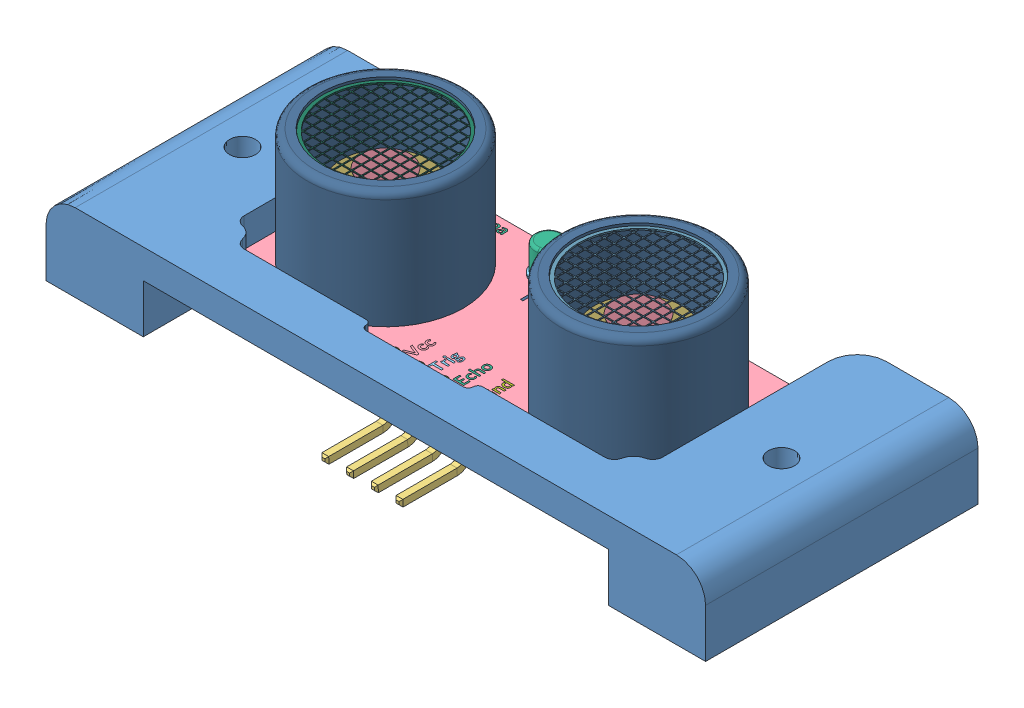
SolidWorks assembly Ultrasonic Assembly, configuration Default. Lengths in mm.
Overall size (67.8 17.46 29.57).
64 component instances, 62 part files, 11 mates.
Components (placement in the parent):
- Ultrasonic Bracket-1: Ultrasonic Bracket [Default] at (0.0374 -5.7361 0.0102) x (-1 0 0) z (0 0 1) size (67.8 8 28)
- HCSR04 Ultrasonic Sensor.stp-1: HCSR04 Ultrasonic Sensor.stp [Default] at (0.0374 -9.7361 0.0102) x (1 0 0) z (0 1 0) size (45 25.57 17.46)
  - HC-04Array.stp-1: HC-04Array.stp [Default] at origin size (10.16 2.54 2.54)
  - HC-04Array001.stp-1: HC-04Array001.stp [Default] at (0 0 1) size (8.32 7.52 6.46)
  - HC-04Placa.stp-1: HC-04Placa.stp [Default] at origin size (45 20 1)
  - HC-04Pad003.stp-1: HC-04Pad003.stp [Default] at (0 0 1) size (10.52 3.38 0.2)
  - HC-04Fillet.stp-1: HC-04Fillet.stp [Default] at (0 0 1) size (10.1 2.84 3)
  - HC-04Array002.stp-1: HC-04Array002.stp [Default] at origin size (9.62 2 1)
  - HC-04Array003.stp-1: HC-04Array003.stp [Default] at (0 0 1) size (28 12 0.8)
  - HC-04Fusion.stp-1: HC-04Fusion.stp [Default] at origin size (6 2 1)
  - HC-04Fillet001.stp-1: HC-04Fillet001.stp [Default] at (0 0 1) size (42 16 12)
  - HC-04Pad005.stp-1: HC-04Pad005.stp [Default] at (0 0 1) size (39.16 13 0.2)
  - HC-04Pad006.stp-1: HC-04Pad006.stp [Default] at (0 0 1) size (35.01 9.04 7)
  - HC-04Fusion001.stp-1: HC-04Fusion001.stp [Default] at (0 0 8) size (31 5 1.5)
  - HC-04Clone_of_Fusion002.stp-1: HC-04Clone_of_Fusion002.stp [Default] at (47.2 -5.5 12.6) size (13 13 0.15)
  - HC-04Clone_of_Fusion003.stp-1: HC-04Clone_of_Fusion003.stp [Default] at (21.2 -5.5 12.6) size (13 13 0.15)
  - HC-04Array005.stp-1: HC-04Array005.stp [Default] at origin size (9.62 2 1)
  - HC-04Array002002.stp-1: HC-04Array002002.stp [Default] at (-5.9 0.1 0.15) size (6.57 1.4 0.56)
  - HC-04Clone_of_Array002002.stp-1: HC-04Clone_of_Array002002.stp [Default] at (-23.9 0.1 0.15) size (6.57 1.4 0.56)
  - HC-04Array002003.stp-1: HC-04Array002003.stp [Default] at (-6.05 0 0.15) size (6.57 1.4 0.56)
  - HC-04Clone_of_Array002003.stp-1: HC-04Clone_of_Array002003.stp [Default] at (-24.05 0 0.15) size (6.57 1.4 0.56)
  - HC-04Integrados.stp-1: HC-04Integrados.stp [Default] at origin size (42.14 9 1)
  - HC-04ShapeString.stp-1: HC-04ShapeString.stp [Default] at (-3.2 -7 1.01) x (0 1 0) z (0 0 1) size (2.53 1.13 0.01)
  - HC-04ShapeString001.stp-1: HC-04ShapeString001.stp [Default] at (-0.6 -7 1.01) x (0 1 0) z (0 0 1) size (2.66 1.45 0.01)
  - HC-04ShapeString002.stp-1: HC-04ShapeString002.stp [Default] at (1.9 -7 1.01) x (0 1 0) z (0 0 1) size (3.21 1.16 0.01)
  - HC-04ShapeString003.stp-1: HC-04ShapeString003.stp [Default] at (4.5 -7 1.01) x (0 1 0) z (0 0 1) size (2.71 1.16 0.01)
  - HC-04ShapeString004.stp-1: HC-04ShapeString004.stp [Default] at (-19.5 -9.3 1.01) size (1.84 2.34 0.01)
  - HC-04ShapeString005.stp-1: HC-04ShapeString005.stp [Default] at (17.5 -9.3 1.01) size (1.82 2.34 0.01)
  - HC-04ShapeString006.stp-1: HC-04ShapeString006.stp [Default] at (-3 3.7 1.01) size (5.52 1.41 0.01)
  - HC-04Pad008.stp-1: HC-04Pad008.stp [Default] at (0 0 -0.01) size (44.56 19.6 1.02)
  - HC-04Scale004.stp-1: HC-04Scale004.stp [Default] at (-1.9 -21.5 -1.5) x (0 1 0) z (0 0 1) size (0.8 1.77 0.5)
  - HC-04Scale027.stp-1: HC-04Scale027.stp [Default] at (-1.9 -10.2323 -1.5) x (0 1 0) z (0 0 1) size (0.8 1.77 0.5)
  - HC-04Scale028.stp-1: HC-04Scale028.stp [Default] at (8.5984 -21.5 -1.5) x (0 1 0) z (0 0 1) size (0.8 1.77 0.5)
  - HC-04Scale029.stp-1: HC-04Scale029.stp [Default] at (8.5984 -19.5867 -1.5) x (0 1 0) z (0 0 1) size (0.8 1.77 0.5)
  - HC-04Scale030.stp-1: HC-04Scale030.stp [Default] at (8.5984 -17.5982 -1.5) x (0 1 0) z (0 0 1) size (0.8 1.77 0.5)
  - HC-04Scale031.stp-1: HC-04Scale031.stp [Default] at (8.5984 -15.6427 -1.5) x (0 1 0) z (0 0 1) size (0.8 1.77 0.5)
  - HC-04Scale032.stp-1: HC-04Scale032.stp [Default] at (8.5984 -11.6848 -1.5) x (0 1 0) z (0 0 1) size (0.8 1.77 0.5)
  - HC-04Scale033.stp-1: HC-04Scale033.stp [Default] at (-26.74 -2 -1.5) x (0 1 0) z (0 0 1) size (0.8 1.85 0.5)
  - HC-04Scale034.stp-1: HC-04Scale034.stp [Default] at (24.9371 -21.5 -1.5) x (0 1 0) z (0 0 1) size (0.8 1.77 0.5)
  - HC-04Scale035.stp-1: HC-04Scale035.stp [Default] at (24.9691 -19.5867 -1.5) x (0 1 0) z (0 0 1) size (0.8 1.77 0.5)
  - HC-04Scale036.stp-1: HC-04Scale036.stp [Default] at (24.9742 -17.5982 -1.5) x (0 1 0) z (0 0 1) size (0.8 1.77 0.5)
  - HC-04Scale037.stp-1: HC-04Scale037.stp [Default] at (-10.4013 -2 -1.5) x (0 1 0) z (0 0 1) size (0.8 1.85 0.5)
  - HC-04Scale038.stp-1: HC-04Scale038.stp [Default] at (-10.4013 -3.9266 -1.5) x (0 1 0) z (0 0 1) size (0.8 1.85 0.5)
  - HC-04Scale039.stp-1: HC-04Scale039.stp [Default] at (-10.4013 -0.0734 -1.5) x (0 1 0) z (0 0 1) size (0.8 1.85 0.5)
  - HC-04Scale040.stp-1: HC-04Scale040.stp [Default] at (24.9742 -9.855 -1.5) x (0 1 0) z (0 0 1) size (0.8 1.77 0.5)
  - HC-04Scale041.stp-1: HC-04Scale041.stp [Default] at (26.5673 -24.0564 -1.5) x (0 1 0) z (0 0 1) size (0.8 1.77 0.5)
  - HC-04Scale042.stp-1: HC-04Scale042.stp [Default] at (26.5673 -7.3333 -1.5) x (0 1 0) z (0 0 1) size (0.8 1.77 0.5)
  - HC-04Scale043.stp-1: HC-04Scale043.stp [Default] at (30.1435 -7.3333 -1.5) x (0 1 0) z (0 0 1) size (0.8 1.77 0.5)
  - HC-04Scale044.stp-1: HC-04Scale044.stp [Default] at (33.5459 -7.3333 -1.5) x (0 1 0) z (0 0 1) size (0.8 1.77 0.5)
  - HC-04Scale045.stp-1: HC-04Scale045.stp [Default] at (37.7181 -11.1827 -1.5) x (0 1 0) z (0 0 1) size (0.8 1.77 0.5)
  - HC-04Scale046.stp-1: HC-04Scale046.stp [Default] at (37.7181 -20.5932 -1.5) x (0 1 0) z (0 0 1) size (0.8 1.77 0.5)
  - HC-04Scale047.stp-1: HC-04Scale047.stp [Default] at (-3.9042 -12.3288 -1.5) x (0 1 0) z (0 0 1) size (0.8 1.85 0.5)
  - HC-04Scale048.stp-1: HC-04Scale048.stp [Default] at (13.5402 13.2894 -1.5) size (0.8 1.85 0.5)
  - HC-04Scale049.stp-1: HC-04Scale049.stp [Default] at (13.5402 23.7909 -1.5) size (0.8 1.85 0.5)
  - HC-04Pad009.stp-1: HC-04Pad009.stp [Default] x (1 0 0) z (0 0 -1) size (42.21 18.43 0.01)
  - HC-04ShapeString007.stp-1: HC-04ShapeString007.stp [Default] at (-3.2 -7 -0.1) x (0 1 0) z (0 0 1) size (2.53 1.13 0.01)
  - HC-04ShapeString008.stp-1: HC-04ShapeString008.stp [Default] at (-0.6 -7 -0.1) x (0 1 0) z (0 0 1) size (2.66 1.45 0.01)
  - HC-04ShapeString009.stp-1: HC-04ShapeString009.stp [Default] at (1.9 -7 -0.1) x (0 1 0) z (0 0 1) size (3.21 1.16 0.01)
  - HC-04ShapeString010.stp-1: HC-04ShapeString010.stp [Default] at (4.5 -7 -0.1) x (0 1 0) z (0 0 1) size (2.71 1.16 0.01)
  - HC-04Fusion002.stp-1: HC-04Fusion002.stp [Default] at origin size (5.7 7.57 0.56)
  - HC-04ShapeString011.stp-1: HC-04ShapeString011.stp [Default] at (-17.5 8.4 1.1) size (7.91 1.16 0.01)
  - HC-04ShapeString012.stp-1: HC-04ShapeString012.stp [Default] at (-7.5 8 -0.1) x (-1 0 0) z (0 0 -1) size (7.91 1.16 0.01)
- DIN934 M2.51-1: DIN934 M2.51 [Default] at (27.7374 -10.8361 0.0102) size (5 2.05 5.77)
- DIN934 M2.51-2: DIN934 M2.51 [Default] at (-27.6626 -10.8361 0.0102) size (5 2.05 5.77)
Mates (geometry in assembly coordinates):
- Parallel2: parallel anti-aligned: plane of Ultrasonic Bracket-1 through (0.0374 -8.7361 0.0102) normal (0 -1 0); plane of HCSR04 Ultrasonic Sensor.stp-1/HC-04Placa.stp-1 through (-22.4626 -8.7361 -9.9898) normal (0 1 0)
- Parallel3: parallel aligned: plane of Ultrasonic Bracket-1 through (0.0374 -8.7361 -13.9898) normal (0 0 -1); plane of HCSR04 Ultrasonic Sensor.stp-1/HC-04Placa.stp-1 through (-22.4626 -9.7361 -9.9898) normal (0 0 -1)
- Coincident5: coincident anti-aligned: plane of Ultrasonic Bracket-1 through (0.0374 -8.7361 0.0102) normal (0 -1 0); plane of HCSR04 Ultrasonic Sensor.stp-1/HC-04Placa.stp-1 through (-22.4626 -8.7361 -9.9898) normal (0 1 0)
- Coincident6: coincident anti-aligned: plane of Ultrasonic Bracket-1 through (0.0374 -10.4861 10.0102) normal (0 0 -1); plane of HCSR04 Ultrasonic Sensor.stp-1/HC-04Placa.stp-1 through (22.5374 -9.7361 10.0102) normal (0 0 1)
- Coincident7: coincident anti-aligned: plane of Ultrasonic Bracket-1 through (0.0374 -5.7361 0.0102) normal (-1 0 0)
- Concentric6: concentric anti-aligned: cylinder of Ultrasonic Bracket-1 through (-27.6626 -13.7361 0.0102) axis (0 1 0) radius 1.35; cylinder of DIN934 M2.51-2 through (-27.6626 -9.8361 0.0102) axis (0 -1 0) radius 1.25
- Parallel5: parallel anti-aligned: plane of Ultrasonic Bracket-1 through (-30.2626 -11.8361 0.0102) normal (1 0 0); plane of DIN934 M2.51-2 through (-30.1626 -9.8361 -1.4331) normal (-1 0 0)
- Coincident10: coincident anti-aligned: plane of Ultrasonic Bracket-1 through (0.0374 -11.8361 0.0102) normal (0 1 0); plane of DIN934 M2.51-2 through (-27.6626 -11.8361 0.0102) normal (0 -1 0)
- Concentric7: concentric anti-aligned: cylinder of Ultrasonic Bracket-1 through (27.7374 -13.7361 0.0102) axis (0 1 0) radius 1.35; cylinder of DIN934 M2.51-1 through (27.7374 -9.8361 0.0102) axis (0 -1 0) radius 1.25
- Parallel6: parallel anti-aligned: plane of Ultrasonic Bracket-1 through (30.3374 -11.8361 0.0102) normal (-1 0 0); plane of DIN934 M2.51-1 through (30.2374 -9.8361 1.4536) normal (1 0 0)
- Coincident12: coincident anti-aligned: plane of Ultrasonic Bracket-1 through (0.0374 -11.8361 0.0102) normal (0 1 0); plane of DIN934 M2.51-1 through (27.7374 -11.8361 0.0102) normal (0 -1 0)
